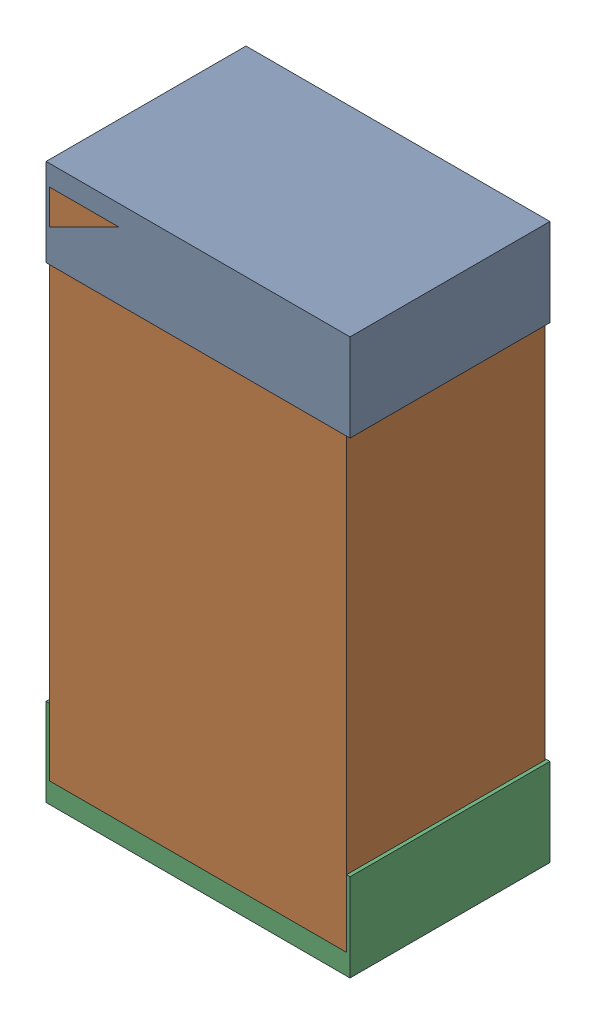
SolidWorks assembly R16Kanaloa_v2.0.0_Motor, configuration Default. Lengths in mm.
Overall size (1.3 2.38 0.85).
6 component instances, 2 part files, 0 mates.
Components (placement in the parent):
- 330415056-1: 330415056 [Default] at (84.836 72.628 -1.9574) size (1.3 0.38 0.85)
  - Extruded_2-1: Extruded_2 [Default] at origin size (1.3 0.38 0.85)
- 334787376-1: 334787376 [Default] at (84.836 71.628 -1.9524) size (1.27 2.2 0.85)
  - Extruded_16-1: Extruded_16 [Default] at origin size (1.27 2.2 0.85)
- 330415056-2: 330415056 [Default] at (84.836 70.628 -1.9574) size (1.3 0.38 0.85)
  - Extruded_2-1: Extruded_2 [Default] at origin size (1.3 0.38 0.85)
